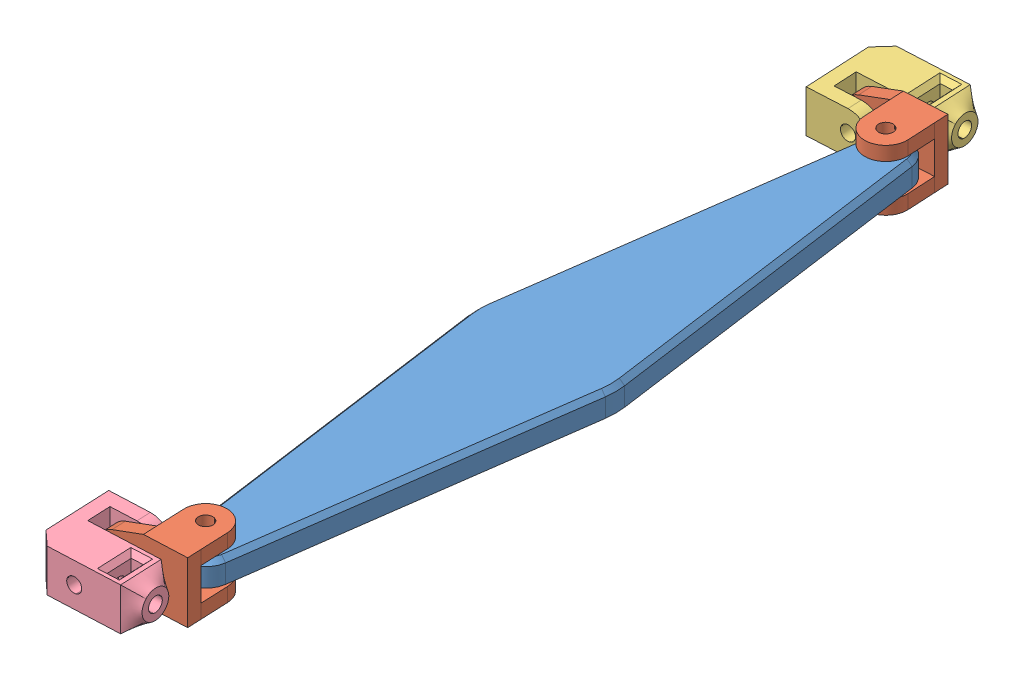
SolidWorks assembly diffSub, configuration Default. Lengths in mm.
Overall size (34.06 13 185.12).
5 component instances, 4 part files, 9 mates.
Components (placement in the parent):
- differentialBar-1: differentialBar [Default] at (-60.7169 0 132.4054) x (1 0 0) z (0 1 0) size (30 156 5)
- differentialHinge-1: differentialHinge [Default] at (109.4283 6 -8.048) x (-0.998631 0 0.052313) z (0 1 0) size (18.65 13.57 13)
- rodHinge-diff-left-1: rodHinge-diff-left [Default] at (109.4846 0 -6.9452) x (0.998698 0 -0.051019) z (0.051019 0 0.998698) size (21.11 9.1 17.1)
- rodHinge-diff-right-1: rodHinge-diff-right [Default] at (109.6477 0 143.6584) x (0.99903 0 -0.044035) z (0.044035 0 0.99903) size (21.11 9.1 17.1)
- differentialHinge-2: differentialHinge [Default] at (108.9918 -1 128.777) x (-0.999086 0 0.042741) z (0 -1 0) size (18.65 13.57 13)
Mates (geometry in assembly coordinates):
- Coincident1: coincident anti-aligned: plane of differentialBar-1 through (-60.7169 0 132.4054) normal (0 -1 0); plane of assembly through (0 0 0) normal (0 1 0)
- Concentric1: concentric: cylinder of differentialBar-1 through (24.2831 -0.001 137.4054) axis (0 1 0) radius 1.55; cylinder of differentialHinge-2 through (24.2831 9 137.4054) axis (0 -1 0) radius 1.55
- Distance1: distance = 1 mm anti-aligned: plane of differentialHinge-2 through (24.2831 6 137.4054) normal (0 -1 0); plane of differentialBar-1 through (-60.7169 5 132.4054) normal (0 1 0)
- Concentric2: concentric: cylinder of rodHinge-diff-right-1 through (14.8229 2.5 139.8302) axis (0.044035 0 0.99903) radius 1.55; cylinder of differentialHinge-2 through (15.1312 2.5 146.8235) axis (-0.044035 0 -0.99903) radius 1.55
- Distance2: distance = 1 mm anti-aligned: plane of rodHinge-diff-right-1 through (109.4275 0 138.6632) normal (0.044035 0 0.99903); plane of differentialHinge-2 through (109.4715 -1 139.6622) normal (-0.044035 0 -0.99903)
- Concentric3: concentric: cylinder of differentialBar-1 through (24.2831 -0.001 -8.5946) axis (0 1 0) radius 1.55; cylinder of differentialHinge-1 through (24.2831 9 -8.5946) axis (0 -1 0) radius 1.55
- Distance3: distance = 1 mm anti-aligned: plane of differentialHinge-1 through (109.4283 6 -8.048) normal (0 -1 0); plane of differentialBar-1 through (-60.7169 5 132.4054) normal (0 1 0)
- Concentric4: concentric: cylinder of differentialHinge-1 through (14.2783 2.5 -17.1011) axis (0.051019 0 0.998698) radius 1.55; cylinder of rodHinge-diff-left-1 through (14.6355 2.5 -10.1102) axis (-0.051019 0 -0.998698) radius 1.55
- Distance4: distance = 1 mm anti-aligned: plane of rodHinge-diff-left-1 through (108.9234 0 -17.9309) normal (-0.051019 0 -0.998698); plane of differentialHinge-1 through (108.8724 6 -18.9296) normal (0.051019 0 0.998698)
